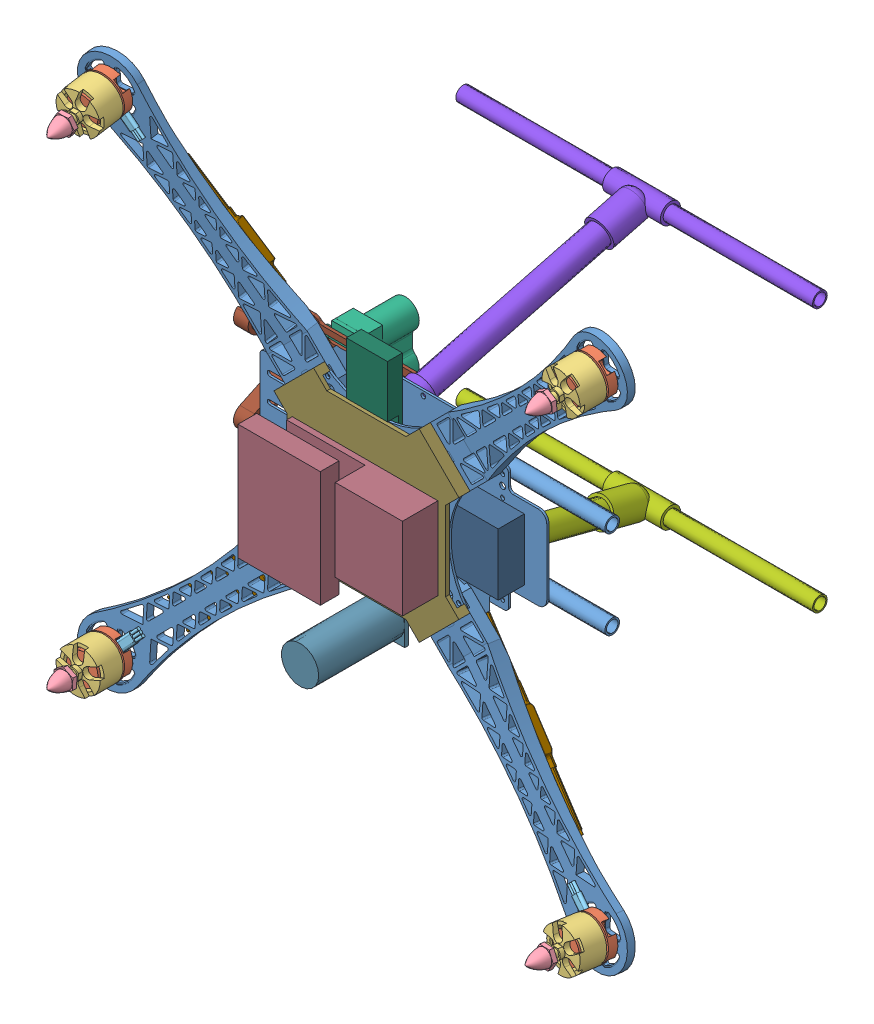
SolidWorks assembly Complete Drone Gazebo - Collision, configuration Default. Lengths in mm.
Overall size (374.52 411.37 390.68).
34 component instances, 15 part files, 50 mates.
Components (placement in the parent):
- S500 Frame-1: S500 Frame [Default] at (72.5801 224.1097 294.7299) size (374.52 374.52 61.06)
- User Library-emaxmodel-mt2213-1: User Library-emaxmodel-mt2213 [По умолчанию] at (238.5265 390.0562 331.8046) x (0.997236 0.002051 0.074267) z (0.007529 -0.997263 -0.073557) size (36.98 47 36.98)
  - User Library-emaxmodel-mt2213_emaxmodel-mt2213-stator-1: User Library-emaxmodel-mt2213_emaxmodel-mt2213-stator [По умолчанию] at origin size (28 21 28)
  - User Library-emaxmodel-mt2213_emaxmodel-mt2213-rotor-1: User Library-emaxmodel-mt2213_emaxmodel-mt2213-rotor [По умолчанию] at (0 7 0) x (0.999557 0 0.02976) z (-0.02976 0 0.999557) size (28 32 28)
  - User Library-emaxmodel-mt2213_emaxmodel-mt2213-cone-1: User Library-emaxmodel-mt2213_emaxmodel-mt2213-cone [По умолчанию] at (0 32 0) size (12 15 13.86)
  - User Library-emaxmodel-mt2213_wires-1: User Library-emaxmodel-mt2213_wires [По умолчанию] at (-15.8508 1.5 15.8508) x (0.707107 0 0.707107) z (-0.707107 0 0.707107) size (7 3 19)
- User Library-emaxmodel-mt2213-2: User Library-emaxmodel-mt2213 [По умолчанию] at (-93.3664 58.1632 331.8046) x (-0.996096 -0.042797 0.07721) z (-0.048269 0.996346 -0.070461) size (36.98 47 36.98)
  - User Library-emaxmodel-mt2213_emaxmodel-mt2213-stator-1: User Library-emaxmodel-mt2213_emaxmodel-mt2213-stator [По умолчанию] at origin size (28 21 28)
  - User Library-emaxmodel-mt2213_emaxmodel-mt2213-rotor-1: User Library-emaxmodel-mt2213_emaxmodel-mt2213-rotor [По умолчанию] at (0 7 0) x (0.999557 0 0.02976) z (-0.02976 0 0.999557) size (28 32 28)
  - User Library-emaxmodel-mt2213_emaxmodel-mt2213-cone-1: User Library-emaxmodel-mt2213_emaxmodel-mt2213-cone [По умолчанию] at (0 32 0) size (12 15 13.86)
  - User Library-emaxmodel-mt2213_wires-1: User Library-emaxmodel-mt2213_wires [По умолчанию] at (-15.8508 1.5 15.8508) x (0.707107 0 0.707107) z (-0.707107 0 0.707107) size (7 3 19)
- User Library-emaxmodel-mt2213-3: User Library-emaxmodel-mt2213 [По умолчанию] at (-93.3664 390.0562 331.8046) x (0.025833 0.997057 0.072181) z (0.99693 -0.020357 -0.075605) size (36.98 47 36.98)
  - User Library-emaxmodel-mt2213_emaxmodel-mt2213-stator-1: User Library-emaxmodel-mt2213_emaxmodel-mt2213-stator [По умолчанию] at origin size (28 21 28)
  - User Library-emaxmodel-mt2213_emaxmodel-mt2213-rotor-1: User Library-emaxmodel-mt2213_emaxmodel-mt2213-rotor [По умолчанию] at (0 7 0) x (0.999557 0 0.02976) z (-0.02976 0 0.999557) size (28 32 28)
  - User Library-emaxmodel-mt2213_emaxmodel-mt2213-cone-1: User Library-emaxmodel-mt2213_emaxmodel-mt2213-cone [По умолчанию] at (0 32 0) size (12 15 13.86)
  - User Library-emaxmodel-mt2213_wires-1: User Library-emaxmodel-mt2213_wires [По умолчанию] at (-15.8508 1.5 15.8508) x (0.707107 0 0.707107) z (-0.707107 0 0.707107) size (7 3 19)
- User Library-emaxmodel-mt2213-4: User Library-emaxmodel-mt2213 [По умолчанию] at (238.5265 58.1632 331.8046) x (0.007659 -0.997178 0.074679) z (-0.997235 -0.013136 -0.073138) size (36.98 47 36.98)
  - User Library-emaxmodel-mt2213_emaxmodel-mt2213-stator-1: User Library-emaxmodel-mt2213_emaxmodel-mt2213-stator [По умолчанию] at origin size (28 21 28)
  - User Library-emaxmodel-mt2213_emaxmodel-mt2213-rotor-1: User Library-emaxmodel-mt2213_emaxmodel-mt2213-rotor [По умолчанию] at (0 7 0) x (0.999557 0 0.02976) z (-0.02976 0 0.999557) size (28 32 28)
  - User Library-emaxmodel-mt2213_emaxmodel-mt2213-cone-1: User Library-emaxmodel-mt2213_emaxmodel-mt2213-cone [По умолчанию] at (0 32 0) size (12 15 13.86)
  - User Library-emaxmodel-mt2213_wires-1: User Library-emaxmodel-mt2213_wires [По умолчанию] at (-15.8508 1.5 15.8508) x (0.707107 0 0.707107) z (-0.707107 0 0.707107) size (7 3 19)
- User Library-LIDAR-Lite_v3-1: User Library-LIDAR-Lite_v3 [Default] at (-16.6199 221.1097 248.205) x (0 -1 0) z (0 0 -1) size (48.5 35.6 40)
- Drone Legs-1: Drone Legs [Default] at (195.2301 134.5438 138.1528) x (0 -0.967884 0.251398) z (-1 0 0) size (19.56 171.15 242.57)
- Drone Legs Right-1: Drone Legs Right [Default] at (195.2301 313.6756 138.1528) x (0 -0.967884 -0.251398) z (-1 0 0) size (19.56 171.15 242.57)
- 30A ESC-1: 30A ESC [Default] at (166.8316 147.9576 305.3085) x (0.707107 0.707107 0) z (0.69963 -0.69963 0.145038) size (28.83 9.95 119.13)
- 30A ESC-2: 30A ESC [Default] at (-3.8513 129.5788 305.3664) x (0.707107 -0.707107 0) z (-0.69963 -0.69963 0.145038) size (28.83 9.95 119.13)
- 30A ESC-3: 30A ESC [Default] at (-4.7202 319.5053 311.4505) x (0.707107 0.707107 0) z (-0.69963 0.69963 0.145038) size (28.83 9.95 119.13)
- 30A ESC-4: 30A ESC [Default] at (167.8781 301.3124 311.4303) x (0.707107 -0.707107 0) z (0.69963 0.69963 0.145038) size (28.83 9.95 119.13)
- LiPO Battery-1: LiPO Battery [Default] at (83.8871 224.0547 296.2299) size (136.91 41.91 17.78)
- S500 Frame - Copy-1: S500 Frame - Copy [Default] at (-56.5902 224.1097 294.7299) size (100 71.1 41.02)
- Gazebo Drone Mount-1: Gazebo Drone Mount [Default] at (72.5801 224.039 323.8499) x (-0.707107 0.707107 0) z (0 0 -1) size (139.7 139.7 7.62)
- Electronics gazebo-1: Electronics gazebo [Default] at (71.6753 223.0343 323.8499) x (0 -1 0) z (0 0 1) size (78.74 101.6 34.29)
- RTK  Antennae Gazebo-1: RTK  Antennae Gazebo [Default] at (76.7679 163.0462 312.1899) x (-1 0 0) z (0 0 1) size (25.4 38.1 60.96)
- Gazebo xbee-1: Gazebo xbee [Default] at (71.4223 291.4188 312.1899) size (27.94 45.72 10.16)
Mates (geometry in assembly coordinates):
- Concentric8: concentric aligned: circle of S500 Frame-1; circle of User Library-emaxmodel-mt2213-3/User Library-emaxmodel-mt2213_emaxmodel-mt2213-stator-1
- Coincident4: coincident anti-aligned: plane of S500 Frame-1 through (-121.5693 391.389 333.9997) normal (0.073913 -0.073913 0.994522); plane of User Library-emaxmodel-mt2213-3/User Library-emaxmodel-mt2213_emaxmodel-mt2213-stator-1 through (-93.3664 390.0562 331.8046) normal (-0.073913 0.073913 -0.994522)
- Concentric9: concentric aligned: circle of S500 Frame-1; circle of User Library-emaxmodel-mt2213-1/User Library-emaxmodel-mt2213_emaxmodel-mt2213-stator-1
- Coincident5: coincident anti-aligned: plane of S500 Frame-1 through (239.8594 418.2591 333.9997) normal (-0.073913 -0.073913 0.994522); plane of User Library-emaxmodel-mt2213-1/User Library-emaxmodel-mt2213_emaxmodel-mt2213-stator-1 through (238.5265 390.0562 331.8046) normal (0.073913 0.073913 -0.994522)
- Concentric10: concentric aligned: circle of S500 Frame-1; circle of User Library-emaxmodel-mt2213-4/User Library-emaxmodel-mt2213_emaxmodel-mt2213-stator-1
- Coincident7: coincident anti-aligned: plane of S500 Frame-1 through (266.7295 56.8304 333.9997) normal (-0.073913 0.073913 0.994522); plane of User Library-emaxmodel-mt2213-4/User Library-emaxmodel-mt2213_emaxmodel-mt2213-stator-1 through (238.5265 58.1632 331.8046) normal (0.073913 -0.073913 -0.994522)
- Concentric11: concentric aligned: circle of S500 Frame-1; circle of User Library-emaxmodel-mt2213-2/User Library-emaxmodel-mt2213_emaxmodel-mt2213-stator-1
- Coincident8: coincident anti-aligned: plane of S500 Frame-1 through (-94.6993 29.9603 333.9997) normal (0.073913 0.073913 0.994522); plane of User Library-emaxmodel-mt2213-2/User Library-emaxmodel-mt2213_emaxmodel-mt2213-stator-1 through (-93.3664 58.1632 331.8046) normal (-0.073913 -0.073913 -0.994522)
- Coincident17: coincident anti-aligned: plane of S500 Frame-1 through (70.0801 224.1097 294.7299) normal (0 0 -1); plane of Drone Legs-1 through (-47.3399 185.3167 294.7299) normal (0 0 1)
- Parallel6: parallel aligned: plane of S500 Frame-1 through (-52.4199 254.1097 281.7299) normal (-1 0 0); plane of Drone Legs-1 through (-47.3399 134.5438 138.1528) normal (-1 0 0)
- Tangent5: tangent: curve of S500 Frame-1 through (35.9491 165.1097 294.7299) axis (1 0 0); edge_curve of Drone Legs-1
- Distance11: distance = 5.08 mm aligned: plane of S500 Frame-1 through (-52.4199 194.1097 281.7299) normal (-1 0 0); plane of Drone Legs-1 through (-47.3399 134.5438 138.1528) normal (-1 0 0)
- Coincident20: coincident anti-aligned: plane of S500 Frame-1 through (70.0801 224.1097 294.7299) normal (0 0 -1); plane of Drone Legs Right-1 through (-47.3399 283.1097 294.7299) normal (0 0 1)
- Distance12: distance = 5.08 mm aligned: plane of Drone Legs Right-1 through (-47.3399 313.6756 138.1528) normal (-1 0 0); plane of S500 Frame-1 through (-52.4199 254.1097 281.7299) normal (-1 0 0)
- Tangent6: tangent: line of S500 Frame-1 through (109.211 283.1097 294.7299) axis (-1 0 0); edge_curve of Drone Legs Right-1
- Coincident21: coincident anti-aligned: plane of 30A ESC-4 through (167.8781 301.3124 311.4303) normal (-0.102557 -0.102557 0.989426); plane of S500 Frame-1 through (120.3098 298.7095 306.2299) normal (0.102557 0.102557 -0.989426)
- Tangent7: tangent anti-aligned: cylinder of S500 Frame-1 through (430.5016 85.5638 323.4423) axis (-0.073913 -0.073913 0.994522) radius 339.0556; plane of 30A ESC-4 through (160.5898 295.1489 304.1315) normal (0.707107 -0.707107 0)
- Lock1: lock: unknown of S500 Frame-1; unknown of 30A ESC-4
- Coincident26: coincident anti-aligned: plane of S500 Frame-1 through (-2.0197 271.8394 306.2299) normal (-0.102557 0.102557 -0.989426); plane of 30A ESC-3 through (-4.7202 319.5053 311.4505) normal (0.102557 -0.102557 0.989426)
- Tangent8: tangent anti-aligned: cylinder of S500 Frame-1 through (211.126 582.0313 323.4423) axis (0.073913 -0.073913 0.994522) radius 339.0556; plane of 30A ESC-3 through (1.4433 312.217 304.1517) normal (0.707107 0.707107 0)
- Lock2: lock: unknown of S500 Frame-1; unknown of 30A ESC-3
- Coincident27: coincident anti-aligned: plane of 30A ESC-1 through (166.2325 148.5568 311.0887) normal (-0.102557 0.102557 0.989426); plane of S500 Frame-1 through (147.1798 176.38 306.2299) normal (0.102557 -0.102557 -0.989426)
- Tangent10: tangent anti-aligned: cylinder of S500 Frame-1 through (-65.9659 -133.8119 323.4423) axis (-0.073913 0.073913 0.994522) radius 339.0556; plane of 30A ESC-1 through (141.3724 138.3468 309.5702) normal (-0.707107 -0.707107 0)
- Lock3: lock: unknown of S500 Frame-1; unknown of 30A ESC-1
- Coincident29: coincident anti-aligned: plane of S500 Frame-1 through (24.8503 149.5099 306.2299) normal (-0.102557 -0.102557 -0.989426); plane of 30A ESC-2 through (-3.2522 130.1779 311.1466) normal (0.102557 0.102557 0.989426)
- Tangent13: tangent anti-aligned: cylinder of S500 Frame-1 through (-285.3415 362.6556 323.4423) axis (0.073913 0.073913 0.994522) radius 339.0556; plane of 30A ESC-2 through (-13.4622 155.038 309.6281) normal (-0.707107 0.707107 0)
- Lock4: lock: unknown of S500 Frame-1; unknown of 30A ESC-2
- Coincident30: coincident anti-aligned: plane of S500 Frame-1 through (70.0801 224.1097 296.2299) normal (0 0 1); plane of LiPO Battery-1 through (83.8871 224.0547 296.2299) normal (0 0 -1)
- Distance15: distance = 15.24 mm aligned: plane of LiPO Battery-1 through (152.3401 203.0997 314.0099) normal (1 0 0); plane of S500 Frame-1 through (167.5801 195.6097 294.7299) normal (1 0 0)
- Distance16: distance = 38.1 mm aligned: plane of LiPO Battery-1 through (152.3401 245.0097 314.0099) normal (0 1 0); plane of S500 Frame-1 through (110.4537 283.1097 294.7299) normal (0 1 0)
- Concentric19: concentric anti-aligned: circle of S500 Frame-1; circle of S500 Frame - Copy-1
- Concentric20: concentric anti-aligned: circle of S500 Frame-1; circle of S500 Frame - Copy-1
- Coincident36: coincident aligned: plane of S500 Frame-1 through (-52.4199 254.1097 281.7299) normal (-1 0 0); plane of S500 Frame - Copy-1 through (-52.4199 224.1097 269.7174) normal (-1 0 0)
- Coincident39: coincident anti-aligned: plane of User Library-LIDAR-Lite_v3-1 through (-16.6199 221.1097 248.205) normal (0 0 1); plane of S500 Frame - Copy-1 through (-12.4199 224.1097 248.205) normal (0 0 -1)
- Concentric27: concentric anti-aligned: circle of User Library-LIDAR-Lite_v3-1; circle of S500 Frame - Copy-1
- Parallel8: parallel aligned: plane of User Library-LIDAR-Lite_v3-1 through (-21.6199 216.8644 233.605) normal (-1 0 0); plane of S500 Frame - Copy-1 through (-62.4199 204.1097 249.205) normal (-1 0 0)
- Coincident40: coincident anti-aligned: plane of S500 Frame-1 through (121.724 174.9658 316.2299) normal (0 0 1); plane of Gazebo Drone Mount-1 through (72.5801 224.039 316.2299) normal (0 0 -1)
- Parallel9: parallel: line of S500 Frame-1 through (133.7448 189.815 316.2299) axis (-0.707107 -0.707107 0); plane of Gazebo Drone Mount-1 through (9.7183 259.96 321.3099) normal (-0.707107 0.707107 0)
- Coincident42: coincident aligned: plane of S500 Frame-1 through (101.2179 279.6176 314.7299) normal (-0.707107 0.707107 0); plane of Gazebo Drone Mount-1 through (99.5208 277.9205 321.3099) normal (-0.707107 0.707107 0)
- Parallel10: parallel aligned: plane of S500 Frame-1 through (43.9422 168.6018 314.7299) normal (0.707107 -0.707107 0); plane of Gazebo Drone Mount-1 through (45.6393 170.1575 321.3099) normal (0.707107 -0.707107 0)
- Coincident44: coincident aligned: plane of S500 Frame-1 through (128.0879 195.4719 314.7299) normal (0.707107 0.707107 0); plane of Gazebo Drone Mount-1 through (126.4616 197.0982 321.3099) normal (0.707107 0.707107 0)
- Coincident46: coincident anti-aligned: plane of Gazebo Drone Mount-1 through (72.5801 224.039 323.8499) normal (0 0 1); plane of Electronics gazebo-1 through (71.6753 223.0343 323.8499) normal (0 0 -1)
- Parallel12: parallel aligned: plane of Gazebo Drone Mount-1 through (126.4616 197.0982 321.3099) normal (1 0 0); plane of Electronics gazebo-1 through (121.2053 195.0943 327.6599) normal (1 0 0)
- Lock5: lock: unknown of Gazebo Drone Mount-1; unknown of Electronics gazebo-1
- Coincident48: coincident anti-aligned: plane of S500 Frame-1 through (72.5801 224.1097 314.7299) normal (0 0 -1); plane of RTK  Antennae Gazebo-1 through (76.7679 163.0462 314.7299) normal (0 0 1)
- Parallel13: parallel aligned: plane of Gazebo Drone Mount-1 through (45.6393 170.1575 321.3099) normal (0 -1 0); plane of RTK  Antennae Gazebo-1 through (64.0679 143.9962 314.7299) normal (0 -1 0)
- Lock6: lock: unknown of Gazebo Drone Mount-1; unknown of RTK  Antennae Gazebo-1
- Coincident50: coincident anti-aligned: plane of S500 Frame-1 through (72.5801 224.1097 314.7299) normal (0 0 -1); plane of Gazebo xbee-1 through (71.4223 291.4188 314.7299) normal (0 0 1)
- Parallel14: parallel aligned: plane of Gazebo Drone Mount-1 through (99.5208 277.9205 321.3099) normal (0 1 0); plane of Gazebo xbee-1 through (85.3923 314.2788 314.7299) normal (0 1 0)
- Lock7: lock: unknown of Gazebo Drone Mount-1; unknown of Gazebo xbee-1
